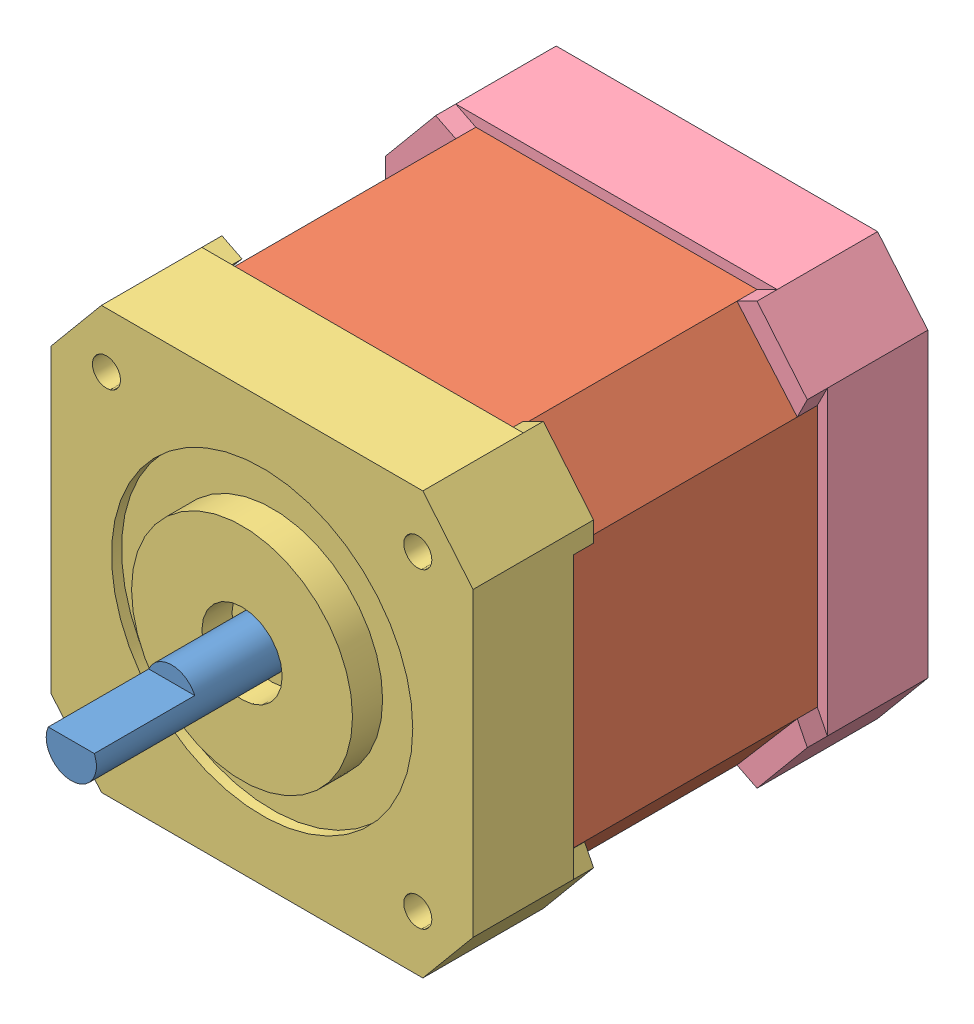
SolidWorks assembly Nema 17, configuration Predeterminado. Lengths in mm.
Overall size (42.28 42 64).
4 component instances, 4 part files, 5 mates.
Components (placement in the parent):
- flecha-1: flecha [Predeterminado] at (-20.8325 5.5864 32.5) size (5 5 24)
- rotor-1: rotor [Predeterminado] at (-20.5547 5.2638 0.5) size (40 40 29)
- Tapa motor-1: Tapa motor [Predeterminado] at (-20.8325 5.5864 37.5) x (-1 0 0) z (0 0 -1) size (42 42 14)
- Base motor-1: Base motor [Predeterminado] at (-20.5547 5.5864 -7.5) size (42 42 12)
Mates (geometry in assembly coordinates):
- Coincidente2: coincident anti-aligned: line of rotor-1 through (-34.5547 25.5864 0.5) axis (1 0 0); line of Base motor-1 through (-6.5547 25.5864 0.5) axis (-1 0 0)
- Coincidente3: coincident anti-aligned: line of rotor-1 through (-0.5547 18.5913 0.5) axis (0 -1 0); line of Base motor-1 through (-0.5547 -7.4185 0.5) axis (0 1 0)
- Coincidente4: coincident anti-aligned: line of rotor-1 through (-34.5547 -14.4136 29.5) axis (1 0 0); line of Tapa motor-1 through (-6.8325 -14.4136 29.5) axis (-1 0 0)
- Coincidente5: coincident aligned: line of rotor-1 through (-34.5547 25.5864 29.5) axis (1 0 0); line of Tapa motor-1 through (-34.8325 25.5864 29.5) axis (1 0 0)
- Coincidente6: coincident aligned: circle of flecha-1; circle of Tapa motor-1
